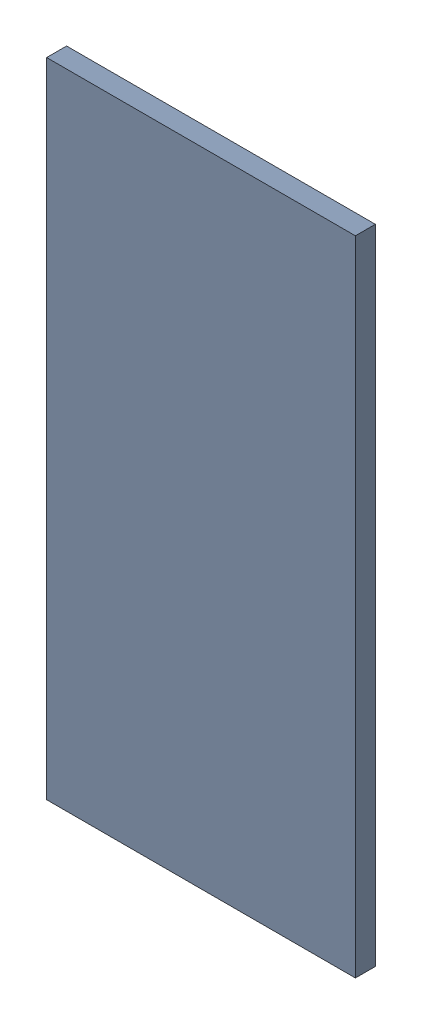
SolidWorks assembly Pad ADXL345-10(20.6mm,55.903mm) on Top Layer, configuration Predeterminado. Lengths in mm.
Overall size (0.55 1.15 0.04).
2 component instances, 1 part files, 0 mates.
Components (placement in the parent):
- Pad ADXL345-10(20.6mm,55.903mm) on Top Layer-1-1: Pad ADXL345-10(20.6mm,55.903mm) on Top Layer-1 [Predeterminado] at (-68.317 -44.187 -0.0457) size (0.55 1.15 0.04)
  - Pad ADXL345-10(20.6mm,55.903mm) on Top Layer-Part-1-1: Pad ADXL345-10(20.6mm,55.903mm) on Top Layer-Part-1 [Predeterminado] at origin size (0.55 1.15 0.04)
